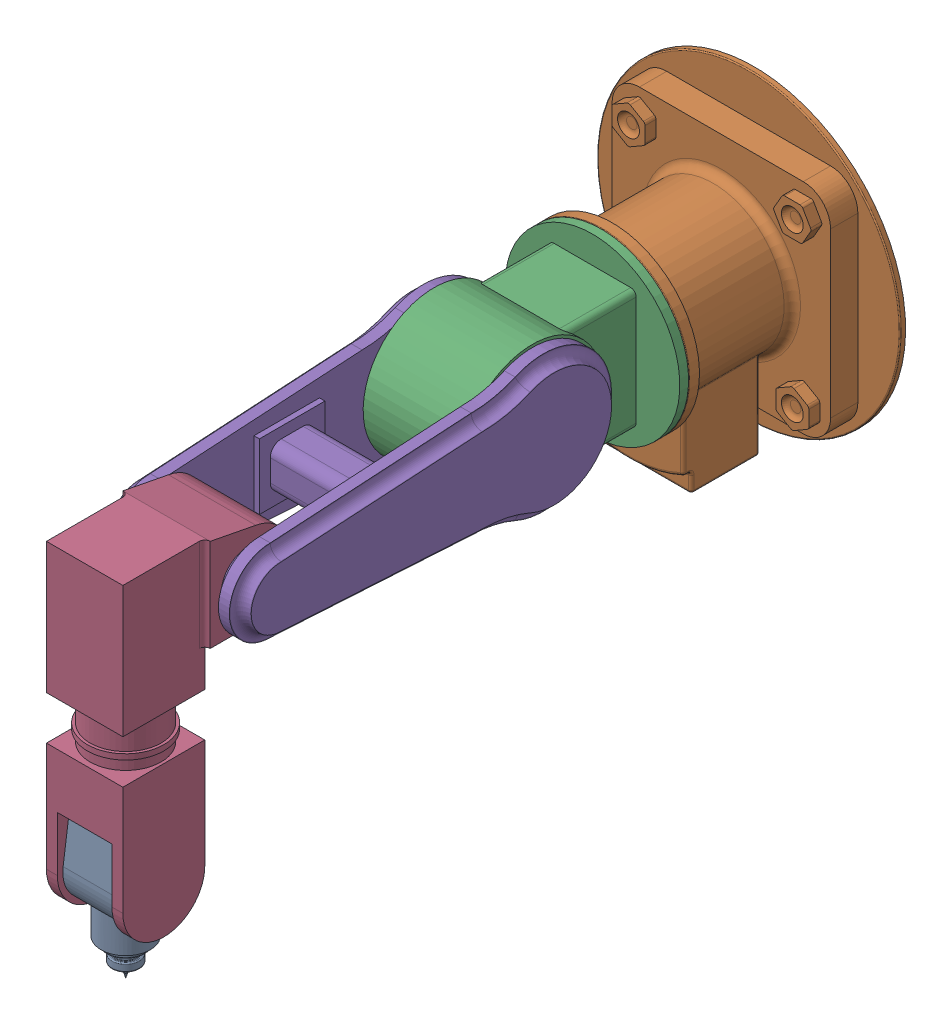
SolidWorks assembly robotAssem3, configuration Default. Lengths in mm.
Overall size (555 880.25 1216).
5 component instances, 5 part files, 12 mates.
Components (placement in the parent):
- link4WRIST-4: link4WRIST [Default] at (-10 -427.4552 1141) x (0 -0.999999 -0.001453) z (-1 0 0) size (359.46 130 100)
- BASE-4: BASE [Default] x (1 0 0) z (0 -1 0) size (555 280 555)
- link1KEY-4: link1KEY [Default] at (0 0 160) x (0 -1 0) z (-1 0 0) size (320 466 320)
- link3ARMREACH-4: link3ARMREACH [Default] at (-10 92.5448 1141) x (0 -1 0) z (-1 0 0) size (595 297.5 160)
- link2ARMCLIP-4: link2ARMCLIP [Default] at (0 0 496) x (0 -1 0) z (-1 0 0) size (250 700 260.14)
Mates (geometry in assembly coordinates):
- Concentric4: concentric aligned: cylinder of link3ARMREACH-4 through (-90.002 -427.4552 1141) axis (1 0 0) radius 50; cylinder of link4WRIST-4 through (-60 -427.4552 1141) axis (1 0 0) radius 50
- Coincident6: coincident anti-aligned: plane of link3ARMREACH-4 through (-60 -427.4552 1141) normal (1 0 0); plane of link4WRIST-4 through (-60 -427.4552 1141) normal (-1 0 0)
- Parallel12: parallel aligned: plane of BASE-4 through (200 200 60) normal (0 1 0); plane of link3ARMREACH-4 through (-10 92.5448 1141) normal (0 1 0)
- Parallel2: parallel aligned: plane of BASE-4 through (200 -200 60) normal (0 -1 0); plane of link2ARMCLIP-4 through (-130.002 -40 726) normal (0 -1 0)
- Concentric1: concentric anti-aligned: cylinder of BASE-4 through (0 0 80) axis (0 0 1) radius 100; cylinder of link1KEY-4 through (0 0 280) axis (0 0 -1) radius 100
- Coincident3: coincident anti-aligned: plane of BASE-4 through (0 0 280) normal (0 0 1); plane of link1KEY-4 through (0 0 280) normal (0 0 -1)
- Parallel1: parallel aligned: plane of BASE-4 through (200 -200 60) normal (1 0 0); plane of link1KEY-4 through (80 -110 626.002) normal (1 0 0)
- Concentric2: concentric aligned: cylinder of link1KEY-4 through (-90 0 496) axis (1 0 0) radius 75; cylinder of link2ARMCLIP-4 through (-90 0 496) axis (1 0 0) radius 75
- Coincident4: coincident anti-aligned: plane of link1KEY-4 through (-90 0 496) normal (-1 0 0); plane of link2ARMCLIP-4 through (-90 0 996) normal (1 0 0)
- Concentric3: concentric aligned: cylinder of link2ARMCLIP-4 through (-90 0 996) axis (1 0 0) radius 50; cylinder of link3ARMREACH-4 through (-90 0 996) axis (1 0 0) radius 50
- Coincident7: coincident anti-aligned: plane of link2ARMCLIP-4 through (-90 0 996) normal (1 0 0); plane of link3ARMREACH-4 through (-90 0 996) normal (-1 0 0)
- Coincident18: coincident: plane of assembly through (0 0 0) normal (0 0 1); plane of BASE-4 through (0 0 0) normal (0 0 -1); plane of assembly
